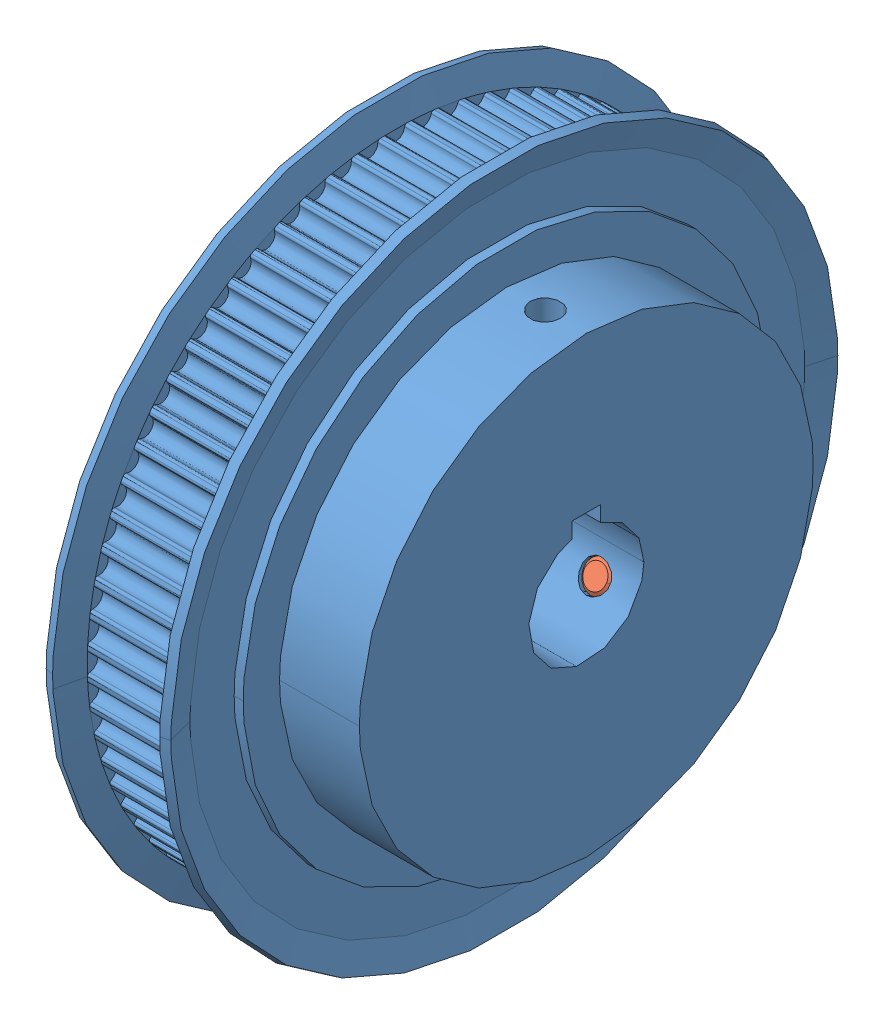
SolidWorks assembly GPA72MR3090_B_NUF, configuration Default. Lengths in mm.
Overall size (23 74 74).
3 component instances, 2 part files, 0 mates.
Components (placement in the parent):
- _GPA72MR3090_B_NUF_b_2-1: _GPA72MR3090_B_NUF_b_2 [Default] at origin size (23 74 74)
- _SET_SCREW_8_32_0_328_4-1: _SET_SCREW_8_32_0_328_4 [Default] at (18.5 7.874 0) x (0 -1 0) z (-1 0 0) size (8.33 4.17 4.17)
- _SET_SCREW_8_32_0_328_4-2: _SET_SCREW_8_32_0_328_4 [Default] at (18.5 -3.175 -5.4993) x (0 0.5 0.866025) z (-1 0 0) size (8.33 4.17 4.17)
